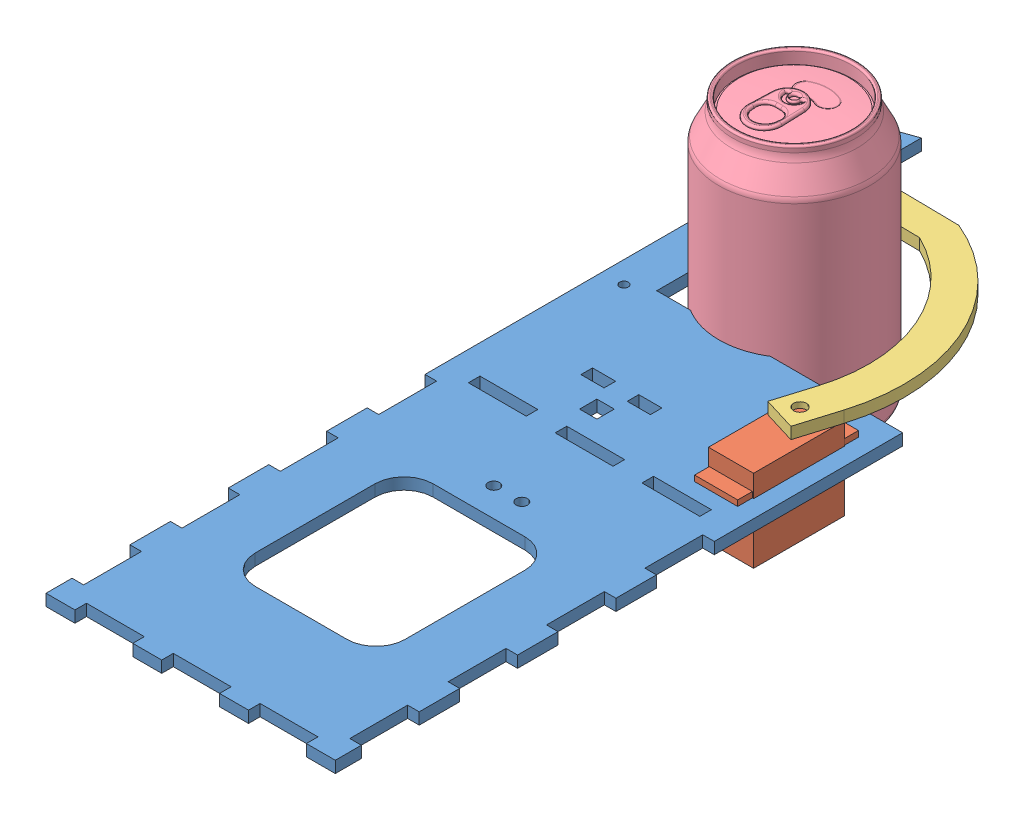
SolidWorks assembly Assem1, configuration Default. Lengths in mm.
Overall size (143.04 120.89 365.21).
4 component instances, 4 part files, 5 mates.
Components (placement in the parent):
- clawbase1.0-2: clawbase1.0 [Default] at (-82.8822 109.086 56.4175) size (127 5.08 365.21)
- standardservo-2: standardservo [Default] at (-2.3642 87.6865 114.2253) x (0 0 1) z (0 1 0) size (52.79 19.81 38.7)
- claw1.0-2: claw1.0 [Default] at (38.7855 126.3834 129.422) x (0.95655 0 0.291569) z (0 1 0) size (118.63 96.83 5.08)
- coke CAN-2: coke CAN [FOR DRINK] at (-50.5151 130.1366 28.3682) size (66.14 120.89 66.14)
Mates (geometry in assembly coordinates):
- Coincident1: coincident anti-aligned: plane of clawbase1.0-2 through (-2.6182 64.6709 74.3092) normal (0 0 1); plane of standardservo-2 through (17.4478 87.6865 74.3092) normal (0 0 -1)
- Coincident2: coincident anti-aligned: plane of clawbase1.0-2 through (17.4478 64.6709 74.3092) normal (-1 0 0); plane of standardservo-2 through (17.4478 87.6865 114.2253) normal (1 0 0)
- Coincident3: coincident anti-aligned: plane of clawbase1.0-2 through (-82.8822 114.166 56.4175) normal (0 1 0); plane of standardservo-2 through (-2.0086 114.166 120.6642) normal (0 -1 0)
- Concentric1: concentric anti-aligned: cylinder of standardservo-2 through (7.5418 126.3834 83.9231) axis (0 -1 0) radius 2.8829; cylinder of claw1.0-2 through (7.5418 115.7971 83.9231) axis (0 1 0) radius 2.8448
- Coincident4: coincident anti-aligned: plane of standardservo-2 through (17.4478 123.8434 74.3092) normal (0 1 0); plane of claw1.0-2 through (-59.7124 123.8434 52.5649) normal (0 -1 0)
